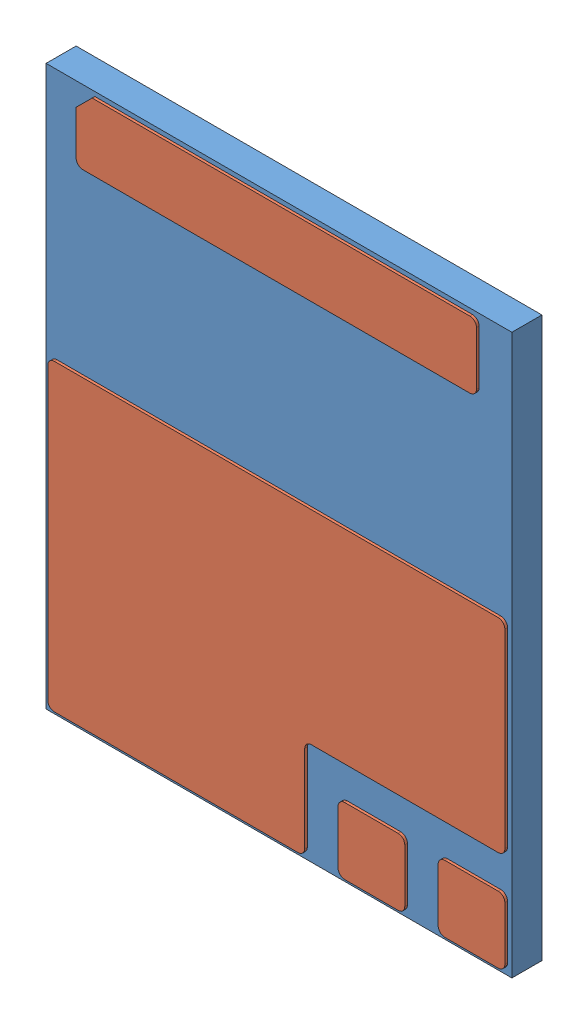
SolidWorks assembly GS66508B, configuration Default. Lengths in mm.
Overall size (6.98 8.38 0.49).
2 component instances, 2 part files, 0 mates.
Components (placement in the parent):
- Package-1: Package [Default] at (-0.2715 0.0344 6.2506) size (6.98 8.38 0.45)
- PCB Bottom CDMM_1-1: PCB Bottom CDMM_1 [Default] at (-0.0115 0.0344 6.7006) size (6.85 8.25 0.04)
